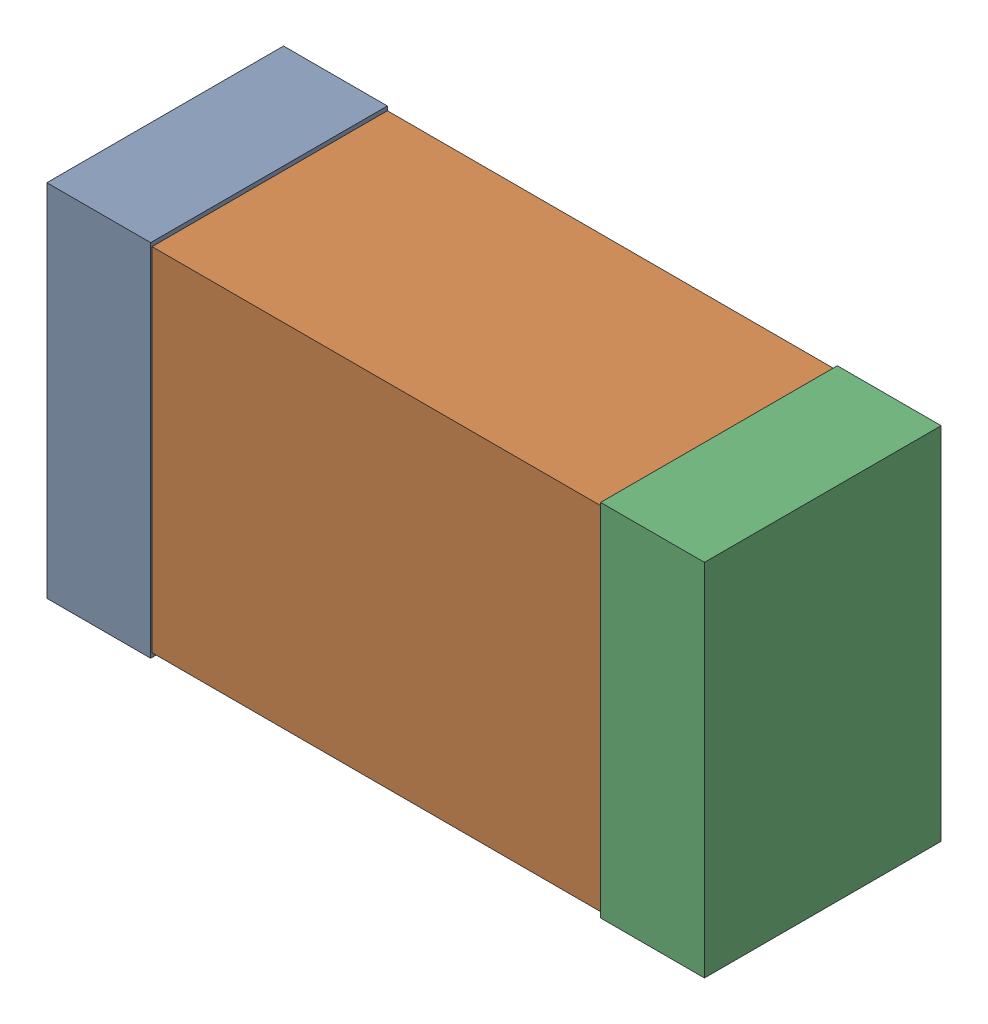
SolidWorks assembly C9_Motor_10Kanaloa_v2.0.0_Motor, configuration Default. Lengths in mm.
Overall size (2.38 1.3 0.85).
6 component instances, 2 part files, 0 mates.
Components (placement in the parent):
- 352877648-1: 352877648 [Default] at (76.681 161.036 0) size (0.38 1.3 0.85)
  - Extruded_14-1: Extruded_14 [Default] at origin size (0.38 1.3 0.85)
- 352877392-1: 352877392 [Default] at (77.681 161.036 0) size (2.2 1.27 0.85)
  - Extruded_15-1: Extruded_15 [Default] at origin size (2.2 1.27 0.85)
- 352877648-2: 352877648 [Default] at (78.681 161.036 0) size (0.38 1.3 0.85)
  - Extruded_14-1: Extruded_14 [Default] at origin size (0.38 1.3 0.85)
